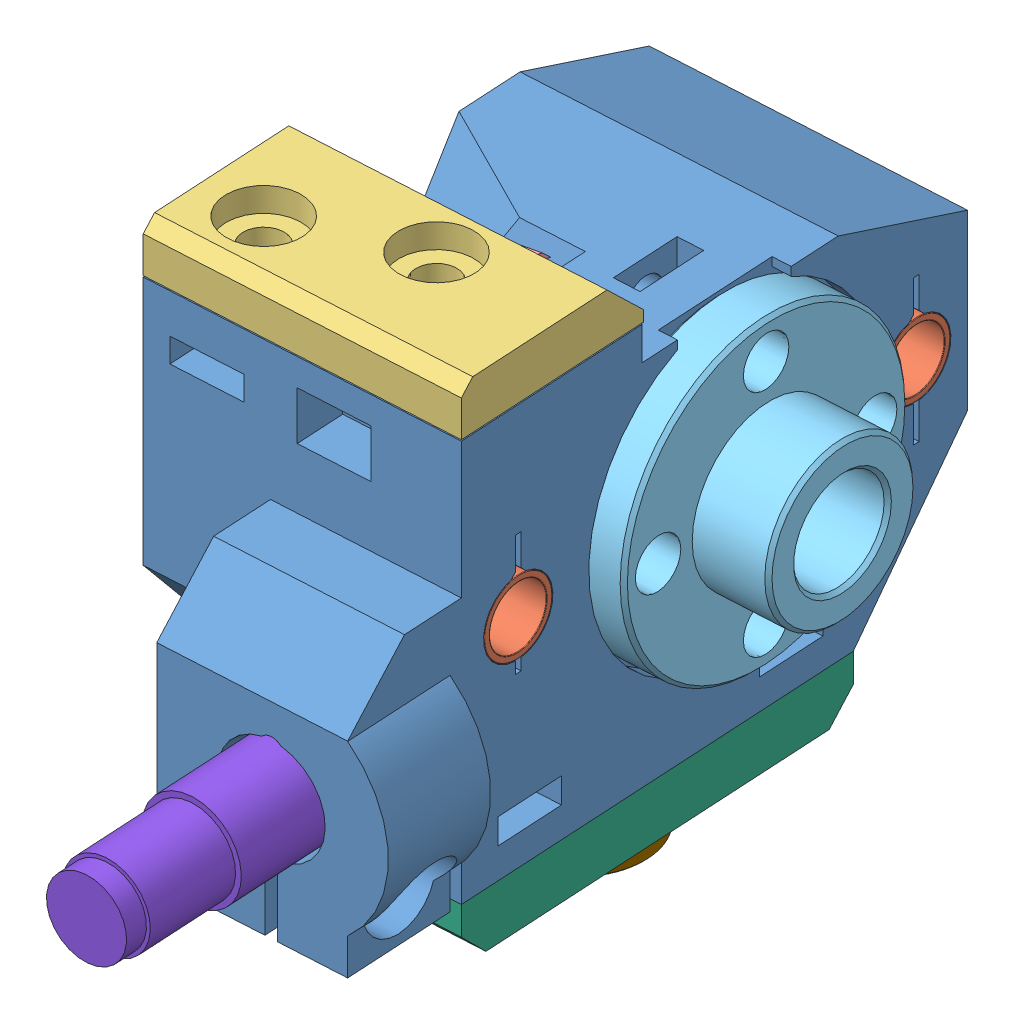
SolidWorks assembly MMU2 finda Selector, configuration Default. Lengths in mm.
Overall size (35.3 43.62 71.45).
10 component instances, 9 part files, 22 mates.
Components (placement in the parent):
- mmu2-selector-finda(M1)-1: mmu2-selector-finda(M1) [Default] at (-43.0577 77.1671 43.6299) x (0.998423 0 -0.056139) z (0.056139 0 0.998423) size (28.2 33.25 54.5)
- Tube 5x6x25bt-1: Tube 5x6x25bt [Default] at (8.2929 34.1671 21.7125) x (0 1 0) z (0.056139 0 0.998423) size (6 25 6)
- Tube 5x6x25bt-2: Tube 5x6x25bt [Default] at (10.2578 34.1671 56.6573) x (0.033082 0.807928 0.588351) z (0.045357 -0.589281 0.806654) size (6 25 6)
- mmu2-blade-holder-1: mmu2-blade-holder [Default] at (-43.0577 77.5171 43.6299) x (0.998423 0 -0.056139) z (0 1 0) size (25 16 4)
- Blade-1: Blade [Default] at (71.6227 49.0171 -0.7074) x (0.973506 0 -0.228661) z (0.228661 0 0.973506) size (15.94 0.5 8.9)
- Z_NUT-1: Z_NUT [Default] at (20.1738 34.1671 37.0697) x (0 1 0) z (0.056139 0 0.998423) size (25 10 25)
- mmu2-selector-front-plate-1: mmu2-selector-front-plate [Default] at (-43.0577 77.1671 43.6299) x (0.998423 0 -0.056139) z (0 -1 0) size (15 34.5 4.5)
- finda Ball-1: finda Ball [Default] at (16.2703 26.1671 47.8058) x (-0.163464 -0.986507 0.009191) z (-0.984951 0.163722 0.055382) size (8 8 8)
- PINDA Probe-1: PINDA Probe [Default] at (17.874 26.1671 76.327) x (-0.434988 -0.900104 0.024458) z (-0.056139 0 -0.998423) size (7.8 7.8 35.75)
- M5 Pressfit Nut-1: M5 Pressfit Nut [94100A140] at (16.0738 10.1671 44.3113) x (0 0 1) z (0 -1 0) size (11 11 5.08)
Mates (geometry in assembly coordinates):
- Concentric1: concentric aligned: cylinder of mmu2-selector-finda(M1)-1 through (-70.1153 34.1671 61.1765) axis (0.998423 0 -0.056139) radius 3.05; cylinder of Tube 5x6x25bt-2 through (-2.2225 34.1671 57.3591) axis (0.998423 0 -0.056139) radius 3
- Concentric2: concentric aligned: cylinder of mmu2-selector-finda(M1)-1 through (-72.0802 34.1671 26.2317) axis (0.998423 0 -0.056139) radius 3.05; cylinder of Tube 5x6x25bt-1 through (-4.1874 34.1671 22.4143) axis (0.998423 0 -0.056139) radius 3
- Coincident1: coincident aligned: plane of Tube 5x6x25bt-1 through (-4.1874 34.1671 22.4143) normal (-0.998423 0 0.056139); plane of Tube 5x6x25bt-2 through (-2.2225 34.1671 57.3591) normal (-0.998423 0 0.056139)
- Coincident2: coincident aligned: plane of mmu2-selector-finda(M1)-1 through (-4.44 16.1671 17.9213) normal (-0.998423 0 0.056139); plane of Tube 5x6x25bt-2 through (-2.2225 34.1671 57.3591) normal (-0.998423 0 0.056139)
- Coincident3: coincident anti-aligned: plane of mmu2-selector-finda(M1)-1 through (-3.383 49.0171 47.4085) normal (0 1 0); plane of Blade-1 through (71.6227 49.0171 -0.7074) normal (0 -1 0)
- Coincident4: coincident anti-aligned: plane of mmu2-selector-finda(M1)-1 through (-1.7179 48.5171 60.7444) normal (0.962305 0 0.271974); plane of Blade-1 through (2.4076 49.5171 46.1474) normal (-0.962305 0 -0.271974)
- Coincident5: coincident anti-aligned: plane of mmu2-selector-finda(M1)-1 through (-1.325 49.0171 56.1701) normal (-0.228661 0 -0.973506); plane of Blade-1 through (-0.3611 49.5171 55.9436) normal (0.228661 0 0.973506)
- Concentric3: concentric aligned: cylinder of mmu2-selector-finda(M1)-1 through (12.5293 50.1671 52.5233) axis (0 -1 0) radius 1.7; cylinder of mmu2-blade-holder-1 through (12.5293 57.5171 52.5233) axis (0 -1 0) radius 1.7
- Concentric4: concentric aligned: cylinder of mmu2-selector-finda(M1)-1 through (2.7696 50.1671 57.0784) axis (0 -1 0) radius 1.7; cylinder of mmu2-blade-holder-1 through (2.7696 57.5171 57.0784) axis (0 -1 0) radius 1.7
- Coincident6: coincident anti-aligned: plane of mmu2-blade-holder-1 through (-2.8401 49.5171 46.3764) normal (0 -1 0); plane of Blade-1 through (71.6227 49.5171 -0.7074) normal (0 1 0)
- Concentric5: concentric aligned: cone of mmu2-selector-finda(M1)-1 through (16.6914 16.1671 55.294) axis (0 1 0); circle of mmu2-selector-front-plate-1
- Concentric6: concentric aligned: cylinder of mmu2-selector-finda(M1)-1 through (15.4002 29.1671 32.3303) axis (0 -1 0) radius 1.65; cylinder of mmu2-selector-front-plate-1 through (15.4002 29.1671 32.3303) axis (0 -1 0) radius 1.65
- Coincident7: coincident anti-aligned: plane of mmu2-selector-finda(M1)-1 through (-4.44 16.1671 17.9213) normal (0 -1 0); plane of mmu2-selector-front-plate-1 through (6.1056 16.1671 27.3442) normal (0 1 0)
- Concentric7: concentric anti-aligned: cylinder of mmu2-selector-finda(M1)-1 through (11.6872 43.6671 37.5469) axis (0.998423 0 -0.056139) radius 1.65; cylinder of Z_NUT-1 through (20.1738 43.6671 37.0697) axis (-0.998423 0 0.056139) radius 2
- Concentric8: concentric anti-aligned: cylinder of mmu2-selector-finda(M1)-1 through (-34.2403 24.6671 40.1293) axis (0.998423 0 -0.056139) radius 1.65; cylinder of Z_NUT-1 through (20.1738 24.6671 37.0697) axis (-0.998423 0 0.056139) radius 2
- Coincident8: coincident anti-aligned: plane of mmu2-selector-finda(M1)-1 through (19.8931 27.1671 32.0776) normal (0.998423 0 -0.056139); plane of Z_NUT-1 through (20.1738 34.1671 37.0697) normal (-0.998423 0 0.056139)
- Coincident9: coincident anti-aligned: line of mmu2-selector-finda(M1)-1 through (16.4949 26.1671 51.7995) axis (0.056139 0 0.998423); line of finda Ball-1 through (16.4949 26.1671 51.7995) axis (-0.056139 0 -0.998423)
- Concentric9: concentric aligned: cylinder of mmu2-selector-finda(M1)-1 through (16.2142 26.1671 46.8074) axis (0.056139 0 0.998423) radius 4.05; cylinder of PINDA Probe-1 through (18.661 26.1671 90.3239) axis (0.056139 0 0.998423) radius 3.9
- Coincident10: coincident aligned: circle of mmu2-selector-finda(M1)-1; plane of finda Ball-1 through (16.4949 26.1671 51.7995) normal (0.056139 0 0.998423)
- Distance1: distance = 7 mm aligned: plane of PINDA Probe-1 through (16.2861 22.6567 78.3531) normal (0.056139 0 0.998423); plane of mmu2-selector-finda(M1)-1 through (8.6038 16.1671 71.774) normal (0.056139 0 0.998423)
- Concentric10: concentric anti-aligned: cone of mmu2-selector-front-plate-1 through (16.0738 11.6671 44.3113) axis (0 1 0); cylinder of M5 Pressfit Nut-1 through (16.0738 13.1671 44.3113) axis (0 -1 0) radius 5.5
- Coincident11: coincident anti-aligned: plane of mmu2-selector-front-plate-1 through (16.0738 13.1671 44.3113) normal (0 -1 0); plane of M5 Pressfit Nut-1 through (16.0738 13.1671 44.3113) normal (0 1 0)
